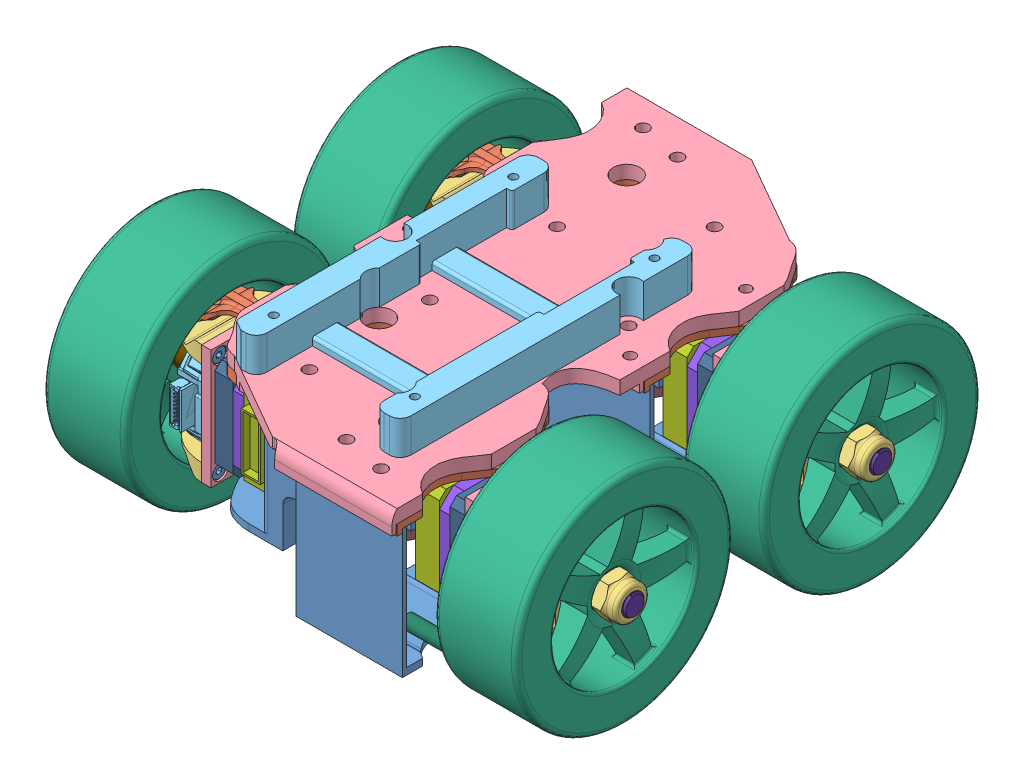
SolidWorks assembly Assembly Dolley chassis, configuration Default. Lengths in mm.
Overall size (185.37 105.78 198.78).
150 component instances, 26 part files, 21 mates.
Components (placement in the parent):
- Module Assembly-1: Module Assembly [Default] at (-66.5 -27.5 -66.5) x (0 0 1) z (-1 0 0) size (68.25 51.28 97.81)
  - Housing-1: Housing [Default] at origin size (64.25 48.5 67.91)
  - Bearing 12x8-1: Bearing 12x8 [Default] at (0 -18.25 0.75) x (-0.914388 0 0.40484) z (-0.40484 0 -0.914388) size (12 3.5 12)
  - Spindle-1: Spindle [Default] at (0 2 0.75) size (49.04 45 20.5)
  - Spindle base-1: Spindle base [Default] at (0 2 -15.25) x (-1 0 0) z (0 -1 0) size (37.62 3.5 44.8)
  - Encoder-1: Encoder [Défaut] at (0 2 -12.48) x (0 1 0) z (0 0 1) size (28.68 37.25 10.4)
  - Wheel-1: Wheel [Default] at (0 2 -8.55) x (0.929787 0.368098 0) z (0.368098 -0.929787 0) size (81.5 31 81.5)
  - Stepper Nema14-1: Stepper Nema14 [Predeterminado] at (4.764 -15.5 -30.1157) x (-1 0 0) z (0 1 0) size (37.8 40 35)
    - nema14_base-1: nema14_base [Predeterminado] at (-12.736 -8.6343 35) size (37.8 9 35)
    - nema14_centro-1: nema14_centro [Predeterminado] at (-12.736 0.3657 35) size (35 4 35)
    - nema14_eje-1: nema14_eje [Predeterminado] at (4.764 -6.6343 17.5) x (0 1 0) z (-0.939004 0 0.343907) size (38 5 5)
    - nema14_techo-1: nema14_techo [Predeterminado] at (-12.736 4.3657 35) size (35 9 35)
  - Servo motor-1: Servo motor [Default] at (-25.7048 26.288 -66.0832) x (0 0 1) z (1 0 0) size (11.5 29.2 32.5) (flexible)
    - TowerPro-SG90-Body-1: TowerPro-SG90-Body [Default] at (13.6721 7.288 30.7048) size (11.5 26 32.5)
    - ServoFinalGear-1: ServoFinalGear [Default] at (13.6721 33.288 25.7048) x (0.607544 0 -0.794286) z (0.794286 0 0.607544) size (4.64 3.2 4.64)
  - Control arm-1: Control arm [Default] at (0 -7.5 -52.4111) x (0.891007 0 0.45399) z (0.45399 0 -0.891007) size (37.9 4.5 7.8)
  - Ball joint assy-1: Ball joint assy [Default] at (-26.7302 -5 -12.8697) x (-0.874356 0 0.485286) z (0.485286 0 0.874356) size (15.43 16.21 22.24) (flexible)
    - Ball-1: Ball [Default] at origin size (5.5 15.11 5.5)
    - Joint-1: Joint [Default] at (-3.8823 13.66 -6.9948) x (0.874356 0 -0.485286) z (0 -1 0) size (5.1 22.6 5.1)
  - Ball joint assy-2: Ball joint assy [Default] at (-26.7302 -5 -66.0308) x (-0.846813 0 0.531891) z (0.531891 0 0.846813) size (16.34 16.21 21.85) (flexible)
    - Ball-1: Ball [Default] at origin size (5.5 15.11 5.5)
    - Joint-1: Joint [Default] at (4.2551 13.66 6.7745) x (-0.846813 0 0.531891) z (0 -1 0) size (5.1 22.6 5.1)
  - Steering rod-1: Steering rod [Default] at (-26.7302 -18.66 -18.4608) x (-0.014502 0.999895 0) z (-0.999895 -0.014502 0) size (3 28.27 3)
  - Wheel adapter-1: Wheel adapter [Default] at (0 2 -13.8175) x (0.291296 -0.956633 0) z (-0.956633 -0.291296 0) size (8.34 40 8.37)
  - Wheel spacer-1: Wheel spacer [Default] at (0 2 12.25) x (0.368098 -0.929787 0) z (0.929787 0.368098 0) size (13.86 8 12)
  - M3x5 din 7984-1: M3x5 din 7984 [Default] at (15.31 20.9 -16.25) x (0.933505 0.358563 0) z (0 0 -1) size (5.5 5.5 7)
  - Housing lid-1: Housing lid [Default] at (0 4 0) x (-1 0 0) z (0 0 1) size (68.25 9.28 69.91)
  - Bearing 12x8-3: Bearing 12x8 [Default] at (0 22.25 0.75) x (-0.914388 0 0.40484) z (0.40484 0 0.914388) size (12 3.5 12)
  - M8 nut-1: M8 nut [Default] at (0 2 16.6825) x (-0.817347 -0.576146 0) z (0 0 1) size (13 16.06 8.5)
  - M3x5 din 7984-2: M3x5 din 7984 [Default] at (15.31 -16.9 -16.25) x (-0.933505 0.358563 0) z (0 0 -1) size (5.5 5.5 7)
  - M3x5 din 7984-3: M3x5 din 7984 [Default] at (-15.31 20.9 -16.25) x (0.933505 -0.358563 0) z (0 0 -1) size (5.5 5.5 7)
  - M3x5 din 7984-4: M3x5 din 7984 [Default] at (-15.31 -16.9 -16.25) x (-0.933505 -0.358563 0) z (0 0 -1) size (5.5 5.5 7)
  - M3x5 din 7984-5: M3x5 din 7984 [Default] at (-13 15 -17.75) x (0.999849 0.017374 0) z (0 0 1) size (5.5 5.5 7)
  - M3x5 din 7984-6: M3x5 din 7984 [Default] at (-13 -11 -17.75) x (-0.999849 0.017374 0) z (0 0 1) size (5.5 5.5 7)
  - M3x5 din 7984-7: M3x5 din 7984 [Default] at (13 15 -17.75) x (0.999849 -0.017374 0) z (0 0 1) size (5.5 5.5 7)
  - M3x5 din 7984-8: M3x5 din 7984 [Default] at (13 -11 -17.75) x (-0.999849 -0.017374 0) z (0 0 1) size (5.5 5.5 7)
- Module Assembly-3: Module Assembly [Default] at (66.5 -27.5 -66.5) x (0 0 -1) z (1 0 0) size (68.25 51.28 97.81)
  - Housing-1: Housing [Default] at origin size (64.25 48.5 67.91)
  - Bearing 12x8-1: Bearing 12x8 [Default] at (0 -18.25 0.75) x (-0.914388 0 0.40484) z (-0.40484 0 -0.914388) size (12 3.5 12)
  - Spindle-1: Spindle [Default] at (0 2 0.75) size (49.04 45 20.5)
  - Spindle base-1: Spindle base [Default] at (0 2 -15.25) x (-1 0 0) z (0 -1 0) size (37.62 3.5 44.8)
  - Encoder-1: Encoder [Défaut] at (0 2 -12.48) x (0 1 0) z (0 0 1) size (28.68 37.25 10.4)
  - Wheel-1: Wheel [Default] at (0 2 -8.55) x (0.929787 0.368098 0) z (0.368098 -0.929787 0) size (81.5 31 81.5)
  - Stepper Nema14-1: Stepper Nema14 [Predeterminado] at (4.764 -15.5 -30.1157) x (-1 0 0) z (0 1 0) size (37.8 40 35)
    - nema14_base-1: nema14_base [Predeterminado] at (-12.736 -8.6343 35) size (37.8 9 35)
    - nema14_centro-1: nema14_centro [Predeterminado] at (-12.736 0.3657 35) size (35 4 35)
    - nema14_eje-1: nema14_eje [Predeterminado] at (4.764 -6.6343 17.5) x (0 1 0) z (-0.939004 0 0.343907) size (38 5 5)
    - nema14_techo-1: nema14_techo [Predeterminado] at (-12.736 4.3657 35) size (35 9 35)
  - Servo motor-1: Servo motor [Default] at (-25.7048 26.288 -66.0832) x (0 0 1) z (1 0 0) size (11.5 29.2 32.5) (flexible)
    - TowerPro-SG90-Body-1: TowerPro-SG90-Body [Default] at (13.6721 7.288 30.7048) size (11.5 26 32.5)
    - ServoFinalGear-1: ServoFinalGear [Default] at (13.6721 33.288 25.7048) x (0.607544 0 -0.794286) z (0.794286 0 0.607544) size (4.64 3.2 4.64)
  - Control arm-1: Control arm [Default] at (0 -7.5 -52.4111) x (0.891007 0 0.45399) z (0.45399 0 -0.891007) size (37.9 4.5 7.8)
  - Ball joint assy-1: Ball joint assy [Default] at (-26.7302 -5 -12.8697) x (-0.874356 0 0.485286) z (0.485286 0 0.874356) size (15.43 16.21 22.24) (flexible)
    - Ball-1: Ball [Default] at origin size (5.5 15.11 5.5)
    - Joint-1: Joint [Default] at (-3.8823 13.66 -6.9948) x (0.874356 0 -0.485286) z (0 -1 0) size (5.1 22.6 5.1)
  - Ball joint assy-2: Ball joint assy [Default] at (-26.7302 -5 -66.0308) x (-0.846813 0 0.531891) z (0.531891 0 0.846813) size (16.34 16.21 21.85) (flexible)
    - Ball-1: Ball [Default] at origin size (5.5 15.11 5.5)
    - Joint-1: Joint [Default] at (4.2551 13.66 6.7745) x (-0.846813 0 0.531891) z (0 -1 0) size (5.1 22.6 5.1)
  - Steering rod-1: Steering rod [Default] at (-26.7302 -18.66 -18.4608) x (-0.014502 0.999895 0) z (-0.999895 -0.014502 0) size (3 28.27 3)
  - Wheel adapter-1: Wheel adapter [Default] at (0 2 -13.8175) x (0.291296 -0.956633 0) z (-0.956633 -0.291296 0) size (8.34 40 8.37)
  - Wheel spacer-1: Wheel spacer [Default] at (0 2 12.25) x (0.368098 -0.929787 0) z (0.929787 0.368098 0) size (13.86 8 12)
  - M3x5 din 7984-1: M3x5 din 7984 [Default] at (15.31 20.9 -16.25) x (0.933505 0.358563 0) z (0 0 -1) size (5.5 5.5 7)
  - Housing lid-1: Housing lid [Default] at (0 4 0) x (-1 0 0) z (0 0 1) size (68.25 9.28 69.91)
  - Bearing 12x8-3: Bearing 12x8 [Default] at (0 22.25 0.75) x (-0.914388 0 0.40484) z (0.40484 0 0.914388) size (12 3.5 12)
  - M8 nut-1: M8 nut [Default] at (0 2 16.6825) x (-0.817347 -0.576146 0) z (0 0 1) size (13 16.06 8.5)
  - M3x5 din 7984-2: M3x5 din 7984 [Default] at (15.31 -16.9 -16.25) x (-0.933505 0.358563 0) z (0 0 -1) size (5.5 5.5 7)
  - M3x5 din 7984-3: M3x5 din 7984 [Default] at (-15.31 20.9 -16.25) x (0.933505 -0.358563 0) z (0 0 -1) size (5.5 5.5 7)
  - M3x5 din 7984-4: M3x5 din 7984 [Default] at (-15.31 -16.9 -16.25) x (-0.933505 -0.358563 0) z (0 0 -1) size (5.5 5.5 7)
  - M3x5 din 7984-5: M3x5 din 7984 [Default] at (-13 15 -17.75) x (0.999849 0.017374 0) z (0 0 1) size (5.5 5.5 7)
  - M3x5 din 7984-6: M3x5 din 7984 [Default] at (-13 -11 -17.75) x (-0.999849 0.017374 0) z (0 0 1) size (5.5 5.5 7)
  - M3x5 din 7984-7: M3x5 din 7984 [Default] at (13 15 -17.75) x (0.999849 -0.017374 0) z (0 0 1) size (5.5 5.5 7)
  - M3x5 din 7984-8: M3x5 din 7984 [Default] at (13 -11 -17.75) x (-0.999849 -0.017374 0) z (0 0 1) size (5.5 5.5 7)
- Module Assembly-6: Module Assembly [Default] at (-66.5 -27.5 26.5) x (0 0 1) z (-1 0 0) size (68.25 51.28 97.81)
  - Housing-1: Housing [Default] at origin size (64.25 48.5 67.91)
  - Bearing 12x8-1: Bearing 12x8 [Default] at (0 -18.25 0.75) x (-0.914388 0 0.40484) z (-0.40484 0 -0.914388) size (12 3.5 12)
  - Spindle-1: Spindle [Default] at (0 2 0.75) size (49.04 45 20.5)
  - Spindle base-1: Spindle base [Default] at (0 2 -15.25) x (-1 0 0) z (0 -1 0) size (37.62 3.5 44.8)
  - Encoder-1: Encoder [Défaut] at (0 2 -12.48) x (0 1 0) z (0 0 1) size (28.68 37.25 10.4)
  - Wheel-1: Wheel [Default] at (0 2 -8.55) x (0.929787 0.368098 0) z (0.368098 -0.929787 0) size (81.5 31 81.5)
  - Stepper Nema14-1: Stepper Nema14 [Predeterminado] at (4.764 -15.5 -30.1157) x (-1 0 0) z (0 1 0) size (37.8 40 35)
    - nema14_base-1: nema14_base [Predeterminado] at (-12.736 -8.6343 35) size (37.8 9 35)
    - nema14_centro-1: nema14_centro [Predeterminado] at (-12.736 0.3657 35) size (35 4 35)
    - nema14_eje-1: nema14_eje [Predeterminado] at (4.764 -6.6343 17.5) x (0 1 0) z (-0.939004 0 0.343907) size (38 5 5)
    - nema14_techo-1: nema14_techo [Predeterminado] at (-12.736 4.3657 35) size (35 9 35)
  - Servo motor-1: Servo motor [Default] at (-25.7048 26.288 -66.0832) x (0 0 1) z (1 0 0) size (11.5 29.2 32.5) (flexible)
    - TowerPro-SG90-Body-1: TowerPro-SG90-Body [Default] at (13.6721 7.288 30.7048) size (11.5 26 32.5)
    - ServoFinalGear-1: ServoFinalGear [Default] at (13.6721 33.288 25.7048) x (0.607544 0 -0.794286) z (0.794286 0 0.607544) size (4.64 3.2 4.64)
  - Control arm-1: Control arm [Default] at (0 -7.5 -52.4111) x (0.891007 0 0.45399) z (0.45399 0 -0.891007) size (37.9 4.5 7.8)
  - Ball joint assy-1: Ball joint assy [Default] at (-26.7302 -5 -12.8697) x (-0.874356 0 0.485286) z (0.485286 0 0.874356) size (15.43 16.21 22.24) (flexible)
    - Ball-1: Ball [Default] at origin size (5.5 15.11 5.5)
    - Joint-1: Joint [Default] at (-3.8823 13.66 -6.9948) x (0.874356 0 -0.485286) z (0 -1 0) size (5.1 22.6 5.1)
  - Ball joint assy-2: Ball joint assy [Default] at (-26.7302 -5 -66.0308) x (-0.846813 0 0.531891) z (0.531891 0 0.846813) size (16.34 16.21 21.85) (flexible)
    - Ball-1: Ball [Default] at origin size (5.5 15.11 5.5)
    - Joint-1: Joint [Default] at (4.2551 13.66 6.7745) x (-0.846813 0 0.531891) z (0 -1 0) size (5.1 22.6 5.1)
  - Steering rod-1: Steering rod [Default] at (-26.7302 -18.66 -18.4608) x (-0.014502 0.999895 0) z (-0.999895 -0.014502 0) size (3 28.27 3)
  - Wheel adapter-1: Wheel adapter [Default] at (0 2 -13.8175) x (0.291296 -0.956633 0) z (-0.956633 -0.291296 0) size (8.34 40 8.37)
  - Wheel spacer-1: Wheel spacer [Default] at (0 2 12.25) x (0.368098 -0.929787 0) z (0.929787 0.368098 0) size (13.86 8 12)
  - M3x5 din 7984-1: M3x5 din 7984 [Default] at (15.31 20.9 -16.25) x (0.933505 0.358563 0) z (0 0 -1) size (5.5 5.5 7)
  - Housing lid-1: Housing lid [Default] at (0 4 0) x (-1 0 0) z (0 0 1) size (68.25 9.28 69.91)
  - Bearing 12x8-3: Bearing 12x8 [Default] at (0 22.25 0.75) x (-0.914388 0 0.40484) z (0.40484 0 0.914388) size (12 3.5 12)
  - M8 nut-1: M8 nut [Default] at (0 2 16.6825) x (-0.817347 -0.576146 0) z (0 0 1) size (13 16.06 8.5)
  - M3x5 din 7984-2: M3x5 din 7984 [Default] at (15.31 -16.9 -16.25) x (-0.933505 0.358563 0) z (0 0 -1) size (5.5 5.5 7)
  - M3x5 din 7984-3: M3x5 din 7984 [Default] at (-15.31 20.9 -16.25) x (0.933505 -0.358563 0) z (0 0 -1) size (5.5 5.5 7)
  - M3x5 din 7984-4: M3x5 din 7984 [Default] at (-15.31 -16.9 -16.25) x (-0.933505 -0.358563 0) z (0 0 -1) size (5.5 5.5 7)
  - M3x5 din 7984-5: M3x5 din 7984 [Default] at (-13 15 -17.75) x (0.999849 0.017374 0) z (0 0 1) size (5.5 5.5 7)
  - M3x5 din 7984-6: M3x5 din 7984 [Default] at (-13 -11 -17.75) x (-0.999849 0.017374 0) z (0 0 1) size (5.5 5.5 7)
  - M3x5 din 7984-7: M3x5 din 7984 [Default] at (13 15 -17.75) x (0.999849 -0.017374 0) z (0 0 1) size (5.5 5.5 7)
  - M3x5 din 7984-8: M3x5 din 7984 [Default] at (13 -11 -17.75) x (-0.999849 -0.017374 0) z (0 0 1) size (5.5 5.5 7)
- Module Assembly-7: Module Assembly [Default] at (66.5 -27.5 26.5) x (0 0 -1) z (1 0 0) size (68.25 51.28 97.81)
  - Housing-1: Housing [Default] at origin size (64.25 48.5 67.91)
  - Bearing 12x8-1: Bearing 12x8 [Default] at (0 -18.25 0.75) x (-0.914388 0 0.40484) z (-0.40484 0 -0.914388) size (12 3.5 12)
  - Spindle-1: Spindle [Default] at (0 2 0.75) size (49.04 45 20.5)
  - Spindle base-1: Spindle base [Default] at (0 2 -15.25) x (-1 0 0) z (0 -1 0) size (37.62 3.5 44.8)
  - Encoder-1: Encoder [Défaut] at (0 2 -12.48) x (0 1 0) z (0 0 1) size (28.68 37.25 10.4)
  - Wheel-1: Wheel [Default] at (0 2 -8.55) x (0.929787 0.368098 0) z (0.368098 -0.929787 0) size (81.5 31 81.5)
  - Stepper Nema14-1: Stepper Nema14 [Predeterminado] at (4.764 -15.5 -30.1157) x (-1 0 0) z (0 1 0) size (37.8 40 35)
    - nema14_base-1: nema14_base [Predeterminado] at (-12.736 -8.6343 35) size (37.8 9 35)
    - nema14_centro-1: nema14_centro [Predeterminado] at (-12.736 0.3657 35) size (35 4 35)
    - nema14_eje-1: nema14_eje [Predeterminado] at (4.764 -6.6343 17.5) x (0 1 0) z (-0.939004 0 0.343907) size (38 5 5)
    - nema14_techo-1: nema14_techo [Predeterminado] at (-12.736 4.3657 35) size (35 9 35)
  - Servo motor-1: Servo motor [Default] at (-25.7048 26.288 -66.0832) x (0 0 1) z (1 0 0) size (11.5 29.2 32.5) (flexible)
    - TowerPro-SG90-Body-1: TowerPro-SG90-Body [Default] at (13.6721 7.288 30.7048) size (11.5 26 32.5)
    - ServoFinalGear-1: ServoFinalGear [Default] at (13.6721 33.288 25.7048) x (0.607544 0 -0.794286) z (0.794286 0 0.607544) size (4.64 3.2 4.64)
  - Control arm-1: Control arm [Default] at (0 -7.5 -52.4111) x (0.891007 0 0.45399) z (0.45399 0 -0.891007) size (37.9 4.5 7.8)
  - Ball joint assy-1: Ball joint assy [Default] at (-26.7302 -5 -12.8697) x (-0.874356 0 0.485286) z (0.485286 0 0.874356) size (15.43 16.21 22.24) (flexible)
    - Ball-1: Ball [Default] at origin size (5.5 15.11 5.5)
    - Joint-1: Joint [Default] at (-3.8823 13.66 -6.9948) x (0.874356 0 -0.485286) z (0 -1 0) size (5.1 22.6 5.1)
  - Ball joint assy-2: Ball joint assy [Default] at (-26.7302 -5 -66.0308) x (-0.846813 0 0.531891) z (0.531891 0 0.846813) size (16.34 16.21 21.85) (flexible)
    - Ball-1: Ball [Default] at origin size (5.5 15.11 5.5)
    - Joint-1: Joint [Default] at (4.2551 13.66 6.7745) x (-0.846813 0 0.531891) z (0 -1 0) size (5.1 22.6 5.1)
  - Steering rod-1: Steering rod [Default] at (-26.7302 -18.66 -18.4608) x (-0.014502 0.999895 0) z (-0.999895 -0.014502 0) size (3 28.27 3)
  - Wheel adapter-1: Wheel adapter [Default] at (0 2 -13.8175) x (0.291296 -0.956633 0) z (-0.956633 -0.291296 0) size (8.34 40 8.37)
  - Wheel spacer-1: Wheel spacer [Default] at (0 2 12.25) x (0.368098 -0.929787 0) z (0.929787 0.368098 0) size (13.86 8 12)
  - M3x5 din 7984-1: M3x5 din 7984 [Default] at (15.31 20.9 -16.25) x (0.933505 0.358563 0) z (0 0 -1) size (5.5 5.5 7)
  - Housing lid-1: Housing lid [Default] at (0 4 0) x (-1 0 0) z (0 0 1) size (68.25 9.28 69.91)
  - Bearing 12x8-3: Bearing 12x8 [Default] at (0 22.25 0.75) x (-0.914388 0 0.40484) z (0.40484 0 0.914388) size (12 3.5 12)
  - M8 nut-1: M8 nut [Default] at (0 2 16.6825) x (-0.817347 -0.576146 0) z (0 0 1) size (13 16.06 8.5)
  - M3x5 din 7984-2: M3x5 din 7984 [Default] at (15.31 -16.9 -16.25) x (-0.933505 0.358563 0) z (0 0 -1) size (5.5 5.5 7)
  - M3x5 din 7984-3: M3x5 din 7984 [Default] at (-15.31 20.9 -16.25) x (0.933505 -0.358563 0) z (0 0 -1) size (5.5 5.5 7)
  - M3x5 din 7984-4: M3x5 din 7984 [Default] at (-15.31 -16.9 -16.25) x (-0.933505 -0.358563 0) z (0 0 -1) size (5.5 5.5 7)
  - M3x5 din 7984-5: M3x5 din 7984 [Default] at (-13 15 -17.75) x (0.999849 0.017374 0) z (0 0 1) size (5.5 5.5 7)
  - M3x5 din 7984-6: M3x5 din 7984 [Default] at (-13 -11 -17.75) x (-0.999849 0.017374 0) z (0 0 1) size (5.5 5.5 7)
  - M3x5 din 7984-7: M3x5 din 7984 [Default] at (13 15 -17.75) x (0.999849 -0.017374 0) z (0 0 1) size (5.5 5.5 7)
  - M3x5 din 7984-8: M3x5 din 7984 [Default] at (13 -11 -17.75) x (-0.999849 -0.017374 0) z (0 0 1) size (5.5 5.5 7)
- Dolly chassis-1: Dolly chassis [Default] x (1 0 0) z (0 1 0) size (93.72 184 8.26)
- Road-1: Road [Default] at (-1.0974 -67.25 -79.593) x (0 0 -1) z (1 0 0) size (303.19 1 155.87) (hidden)
- Road-2: Road [Default] at (-1.0974 17.75 -79.593) x (0 0 -1) z (1 0 0) size (303.19 1 155.87) (hidden)
- Fifth wheel adapter-1: Fifth wheel adapter [Default] at (0 5 -58) x (-1 0 0) z (0 0 -1) size (64 12.75 112)
- Pickup part 1-1: Pickup part 1 [Default] at (0 5 0) x (1 0 0) z (0 1 0) size (68.84 120 7) (hidden)
- Pickup part 2-1: Pickup part 2 [Default] at (-58.9105 0.75 242.9177) x (1 0 0) z (0 1 0) size (51.91 338.54 4.25) (hidden)
Mates (geometry in assembly coordinates):
- Distance2: distance = 66.5 mm: plane of assembly through (0 0 0) normal (1 0 0); plane of Module Assembly-1/Housing-1 through (-66.5 -27.5 -66.5) normal (-1 0 0)
- Distance3: distance = 66.5 mm: plane of assembly through (0 0 0) normal (1 0 0); plane of Module Assembly-3/Housing-1 through (66.5 -27.5 -66.5) normal (1 0 0)
- Coincident11: coincident: plane of Module Assembly-1/Housing-1 through (-66.5 -27.5 -66.5) normal (0 0 1); plane of Module Assembly-3/Housing-1 through (66.5 -27.5 -66.5) normal (0 0 -1)
- InPlace2: in place: plane of Dolly chassis-1 through (0 0 0) normal (0 1 0); moOrthogonalPlaneRef_w of Dolly chassis-1 through (0 0 0) normal (0 0 -1); plane of Dolly chassis-1 through (0 0 0) normal (1 0 0); unknown of Dolly chassis-1
- Coincident109: coincident: plane of ?; plane of assembly
- Coincident110: coincident: plane of Dolly chassis-1 through (0 0 0) normal (0 0 -1); moOrthogonalPlaneRef_w of assembly
- Coincident111: coincident: plane of Dolly chassis-1 through (0 0 0) normal (1 0 0); moOrthogonalPlaneRef_w of assembly
- Distance4: distance = 0.5 mm: plane of Module Assembly-1/Housing lid-1 through (-66.5 -4 -110) normal (0 0 -1); plane of Dolly chassis-1 through (-46.8389 -3 -110.5) normal (0 0 1)
- Coincident14: coincident: plane of Module Assembly-1/Housing lid-1 through (-66.5 0 -66.5) normal (0 1 0); plane of Dolly chassis-1 through (0 0 0) normal (0 -1 0)
- Coincident15: coincident: plane of Module Assembly-7/Housing lid-1 through (66.5 0 26.5) normal (0 1 0); plane of Dolly chassis-1 through (0 0 0) normal (0 -1 0)
- Tangent1: tangent: cylinder of Module Assembly-7/Wheel-1 through (88.95 -25.5 26.5) axis (-1 0 0) radius 40.75; plane of Road-1 through (-1.0974 -66.25 -79.593) normal (0 1 0)
- Coincident17: coincident: plane of Dolly chassis-1 through (2.8389 -3 72) normal (0 0 1); plane of Road-1 through (76.8389 -66.25 72) normal (0 0 1)
- Distance5: distance = 30 mm: plane of Road-1 through (76.8389 -66.25 72) normal (1 0 0); plane of Dolly chassis-1 through (46.8389 5 0) normal (1 0 0)
- Coincident19: coincident: plane of Dolly chassis-1 through (0 5 0) normal (0 1 0); plane of Fifth wheel adapter-1 through (0 5 -58) normal (0 -1 0)
- Parallel3: parallel: plane of Dolly chassis-1 through (2.8389 -3 72) normal (0 0 1); plane of Fifth wheel adapter-1 through (0 17.75 54) normal (0 0 1)
- Coincident23: coincident: plane of Dolly chassis-1 through (0 0 0) normal (1 0 0); plane of Fifth wheel adapter-1 through (0 5 -58) normal (-1 0 0)
- Distance6: distance = 46.5 mm: plane of Fifth wheel adapter-1 through (0 5 -20) normal (0 0 -1); plane of Module Assembly-1/Housing-1 through (-66.5 -27.5 -66.5) normal (0 0 1)
- InPlace3: in place: plane of Dolly chassis-1 through (0 5 0) normal (0 1 0); plane of Pickup part 1-1 through (0 5 0) normal (0 1 0); plane of Dolly chassis-1 through (0 5 0) normal (0 1 0); plane of Pickup part 1-1 through (0 5 0) normal (0 0 -1); plane of Dolly chassis-1 through (0 5 0) normal (0 1 0); plane of Pickup part 1-1 through (0 5 0) normal (1 0 0); plane of Dolly chassis-1 through (0 5 0) normal (0 1 0); unknown of Pickup part 1-1
- Coincident25: coincident: plane of ?; plane of ?
- Coincident26: coincident: moOrthogonalPlaneRef_w of Dolly chassis-1 through (0 5 0) normal (0 0 -1); plane of Pickup part 1-1 through (0 5 0) normal (0 0 -1)
- Coincident27: coincident: moOrthogonalPlaneRef_w of Dolly chassis-1 through (0 5 0) normal (-1 0 0); plane of Pickup part 1-1 through (0 5 0) normal (1 0 0)
